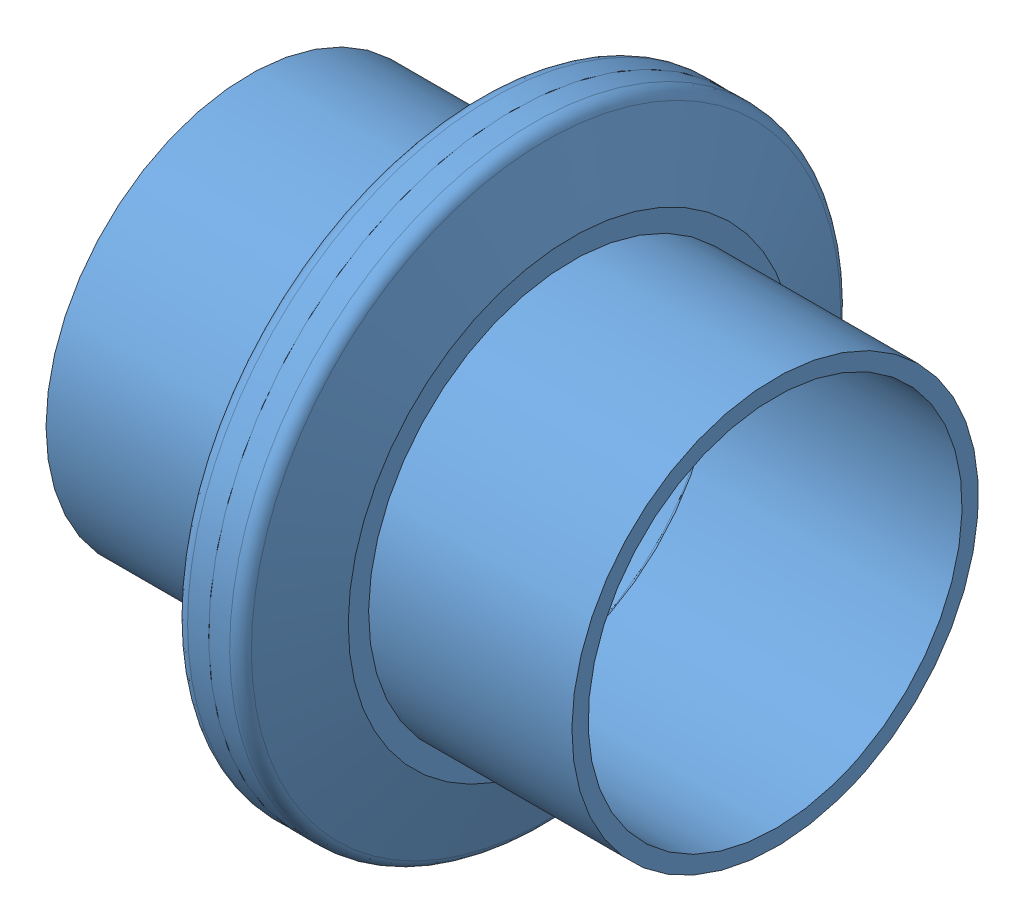
SolidWorks assembly Assem1, configuration Default. Lengths in mm.
Overall size (49.28 74.31 74.31).
2 component instances, 1 part files, 2 mates.
Components (placement in the parent):
- FemaleFlange-1: FemaleFlange [Default] at (-82.1258 38.0488 10.9863) size (24.64 56.9 56.9)
- FemaleFlange-2: FemaleFlange [Default] at (-32.8498 38.0488 10.9863) x (-1 0 0) z (0 0.924225 0.381849) size (24.64 56.9 56.9)
Mates (geometry in assembly coordinates):
- Concentric1: concentric anti-aligned: cylinder of FemaleFlange-1 through (-63.0758 38.0488 10.9863) axis (-1 0 0) radius 17.526; cylinder of FemaleFlange-2 through (-51.8998 38.0488 10.9863) axis (1 0 0) radius 17.526
- Coincident1: coincident anti-aligned: plane of FemaleFlange-1 through (-57.4878 38.0488 10.9863) normal (1 0 0); plane of FemaleFlange-2 through (-57.4878 38.0488 10.9863) normal (-1 0 0)
